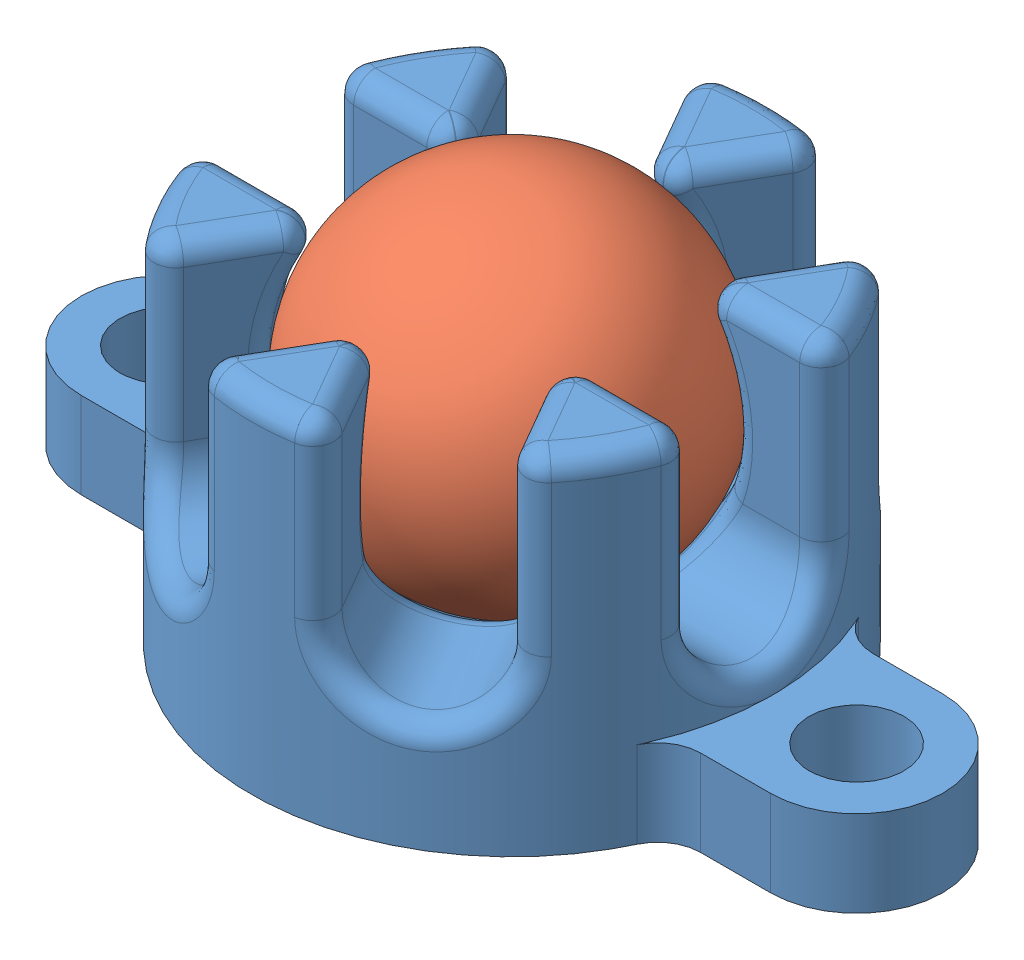
SolidWorks assembly caster-wheel-custom, configuration Default. Lengths in mm.
Overall size (20 9.35 12.1).
2 component instances, 2 part files, 2 mates.
Components (placement in the parent):
- caster-wheel-case-1: caster-wheel-case [Default] at origin size (20 7.99 12.1)
- ball-1: ball [Default] at (0 5.35 0) size (8 8 8)
Mates (geometry in assembly coordinates):
- Coincident1: coordinate: point of caster-wheel-case-1
- Concentric1: concentric: sphere of caster-wheel-case-1; sphere of ball-1
